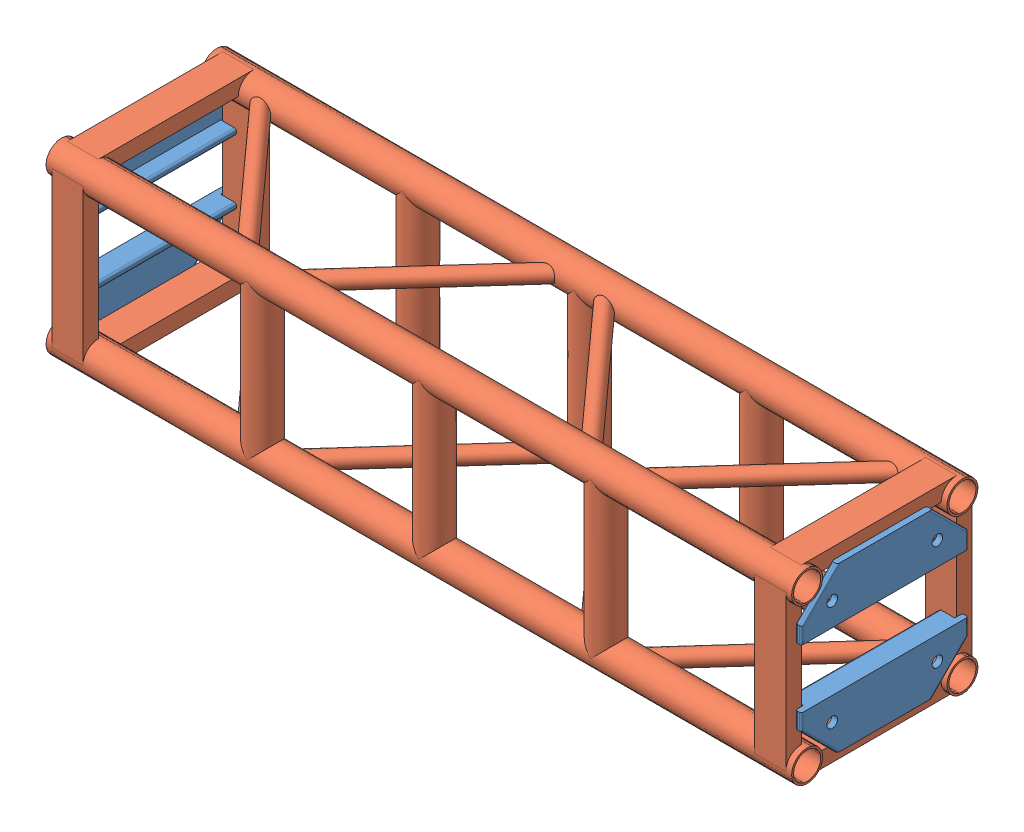
SolidWorks assembly FE-01002, configuration Default. Lengths in mm.
Overall size (1219.2 304.8 304.81).
5 component instances, 2 part files, 0 mates.
Components (placement in the parent):
- Connection Plate _ TS Standard-1: Connection Plate _ TS Standard [Default] at (-592.1375 -90.7415 0) x (0 0 -1) z (1 0 0) size (273.05 85.72 34.92)
- Connection Plate _ TS Standard-2: Connection Plate _ TS Standard [Default] at (-592.1375 90.7415 0) x (0 0 1) z (1 0 0) size (273.05 85.72 34.92)
- Connection Plate _ TS Standard-3: Connection Plate _ TS Standard [Default] at (592.1375 90.7415 0) x (0 0 -1) z (-1 0 0) size (273.05 85.72 34.92)
- Connection Plate _ TS Standard-4: Connection Plate _ TS Standard [Default] at (592.1375 -90.7415 0) x (0 0 1) z (-1 0 0) size (273.05 85.72 34.92)
- FE-01002-01-1: FE-01002-01 [Default<As Machined>] at origin size (1219.2 304.8 304.81)
